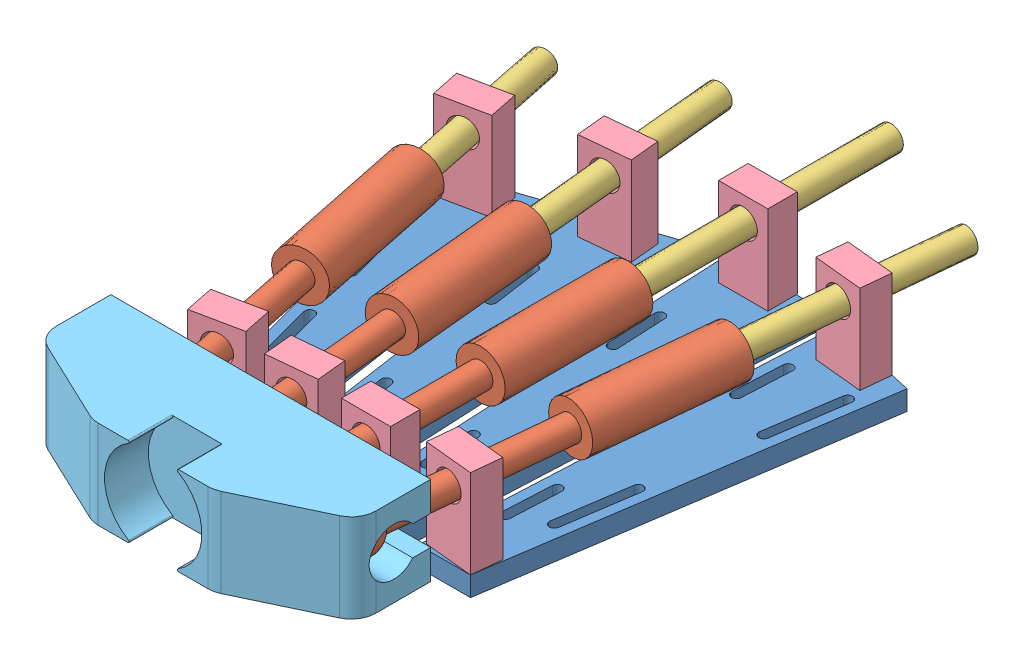
SolidWorks assembly Back_of_hand, configuration Default. Lengths in mm.
Overall size (87.18 26 139.8).
18 component instances, 5 part files, 38 mates.
Components (placement in the parent):
- Back_of_hand_base-1: Back_of_hand_base [Default] at origin size (87.18 4 82.73)
- Back_of_hand_diff_rod_outer-1: Back_of_hand_diff_rod_outer [Default] at (-35.6285 17 10.2401) x (-0.935794 -0.294771 0.193391) z (0.202383 0 0.979306) size (10 10 74.5)
- Back_of_hand_diff_rod_inner-1: Back_of_hand_diff_rod_inner [Ring] at (-17.9319 17 -4.3231) x (0.01106 -0.999938 -0.001065) z (0.095828 0 0.995398) size (5 5 50)
- Back_of_hand_diff_rod_outer-2: Back_of_hand_diff_rod_outer [Default] at (-16.6074 17 9.4356) x (0.587338 0.807364 -0.056544) z (0.095828 0 0.995398) size (10 10 74.5)
- Back_of_hand_diff_rod_inner-2: Back_of_hand_diff_rod_inner [Pinky] at (-38.3595 17 -2.9749) x (-0.272097 0.960626 0.056231) z (0.202383 0 0.979306) size (5 5 40)
- Back_of_hand_diff_rod_inner-3: Back_of_hand_diff_rod_inner [Middle] at (2.1823 17 -4.1955) x (-0.866819 -0.498624 -0.000178) z (-0.000206 0 1) size (5 5 60)
- Back_of_hand_diff_rod_outer-3: Back_of_hand_diff_rod_outer [Default] at (2.1796 17 9.2055) x (0.99957 0.029339 0.000206) z (-0.000206 0 1) size (10 10 74.5)
- Back_of_hand_diff_rod_inner-4: Back_of_hand_diff_rod_inner [Index] at (22.9884 17 -4.1612) x (0.887656 -0.452116 0.087506) z (-0.098105 0 0.995176) size (5 5 50)
- Back_of_hand_diff_rod_outer-4: Back_of_hand_diff_rod_outer [Default] at (21.647 17 9.4467) x (0.691392 -0.719257 0.068158) z (-0.098105 0 0.995176) size (10 10 74.5)
- Back_of_hand_bar_holder-1: Back_of_hand_bar_holder [Default] at (-20.8258 17 -34.3829) x (0.995398 0 -0.095828) z (0.095828 0 0.995398) size (10 18 6)
- Back_of_hand_bar_holder-2: Back_of_hand_bar_holder [Default] at (-14.0453 17 36.0485) x (0.995398 0 -0.095828) z (0.095828 0 0.995398) size (10 18 6)
- Back_of_hand_bar_holder-3: Back_of_hand_bar_holder [Default] at (19.0255 17 36.0384) x (0.995176 0 0.098105) z (-0.098105 0 0.995176) size (10 18 6)
- Back_of_hand_bar_holder-4: Back_of_hand_bar_holder [Default] at (26.1272 17 -36.0008) x (0.995176 0 0.098105) z (-0.098105 0 0.995176) size (10 18 6)
- Back_of_hand_bar_holder-5: Back_of_hand_bar_holder [Default] at (2.1897 17 -40.1452) x (1 0 0.000206) z (-0.000206 0 1) size (10 18 6)
- Back_of_hand_bar_holder-6: Back_of_hand_bar_holder [Default] at (2.1739 17 36.501) x (1 0 0.000206) z (-0.000206 0 1) size (10 18 6)
- Back_of_hand_bar_holder-7: Back_of_hand_bar_holder [Default] at (-43.411 17 -27.4181) x (0.979306 0 -0.202383) z (0.202383 0 0.979306) size (10 18 6)
- Back_of_hand_bar_holder-8: Back_of_hand_bar_holder [Default] at (-30.3851 17 35.6122) x (0.979306 0 -0.202383) z (0.202383 0 0.979306) size (10 18 6)
- Back_of_hand_bar_connector-1: Back_of_hand_bar_connector [Default] at (-40.4652 17 59.2055) size (65 18 23.9)
Mates (geometry in assembly coordinates):
- Coincident2: coordinate: point of Back_of_hand_base-1; point of assembly
- Concentric1: concentric anti-aligned: cylinder of Back_of_hand_diff_rod_inner-4 through (29.1691 17 -66.8573) axis (0.098105 0 -0.995176) radius 2.5; cylinder of Back_of_hand_diff_rod_outer-4 through (17.004 17 56.5449) axis (-0.098105 0 0.995176) radius 2.5
- Concentric2: concentric anti-aligned: cylinder of Back_of_hand_diff_rod_inner-1 through (-23.9691 17 -67.0332) axis (-0.095828 0 -0.995398) radius 2.5; cylinder of Back_of_hand_diff_rod_outer-2 through (-12.0722 17 56.5443) axis (0.095828 0 0.995398) radius 2.5
- Concentric3: concentric anti-aligned: cylinder of Back_of_hand_diff_rod_outer-1 through (-26.0504 17 56.5873) axis (0.202383 0 0.979306) radius 2.5; cylinder of Back_of_hand_diff_rod_inner-2 through (-51.1097 17 -64.6712) axis (-0.202383 0 -0.979306) radius 2.5
- Concentric4: concentric anti-aligned: cylinder of Back_of_hand_diff_rod_inner-3 through (2.1953 17 -67.1955) axis (0.000206 0 -1) radius 2.5; cylinder of Back_of_hand_diff_rod_outer-3 through (2.1698 17 56.532) axis (-0.000206 0 1) radius 2.5
- Concentric5: concentric anti-aligned: cylinder of Back_of_hand_diff_rod_outer-1 through (-26.0504 17 56.5873) axis (0.202383 0 0.979306) radius 2.5; cylinder of Back_of_hand_bar_holder-8 through (-29.1708 17 41.4881) axis (-0.202383 0 -0.979306) radius 2.875
- Concentric6: concentric aligned: cylinder of Back_of_hand_diff_rod_inner-2 through (-51.1097 17 -64.6712) axis (-0.202383 0 -0.979306) radius 2.5; cylinder of Back_of_hand_bar_holder-7 through (-42.1967 17 -21.5423) axis (-0.202383 0 -0.979306) radius 2.875
- Concentric7: concentric aligned: cylinder of Back_of_hand_diff_rod_inner-1 through (-23.9691 17 -67.0332) axis (-0.095828 0 -0.995398) radius 2.5; cylinder of Back_of_hand_bar_holder-1 through (-20.2508 17 -28.4105) axis (-0.095828 0 -0.995398) radius 2.875
- Concentric8: concentric anti-aligned: cylinder of Back_of_hand_diff_rod_outer-3 through (2.1698 17 56.532) axis (-0.000206 0 1) radius 2.5; cylinder of Back_of_hand_bar_holder-6 through (2.1727 17 42.501) axis (0.000206 0 -1) radius 2.875
- Concentric9: concentric aligned: cylinder of Back_of_hand_diff_rod_inner-3 through (2.1953 17 -67.1955) axis (0.000206 0 -1) radius 2.5; cylinder of Back_of_hand_bar_holder-5 through (2.1885 17 -34.1452) axis (0.000206 0 -1) radius 2.875
- Concentric10: concentric aligned: cylinder of Back_of_hand_diff_rod_inner-4 through (29.1691 17 -66.8573) axis (0.098105 0 -0.995176) radius 2.5; cylinder of Back_of_hand_bar_holder-3 through (18.4369 17 42.0095) axis (0.098105 0 -0.995176) radius 2.875
- Concentric11: concentric aligned: cylinder of Back_of_hand_diff_rod_inner-4 through (29.1691 17 -66.8573) axis (0.098105 0 -0.995176) radius 2.5; cylinder of Back_of_hand_bar_holder-4 through (25.5386 17 -30.0297) axis (0.098105 0 -0.995176) radius 2.875
- Concentric12: concentric: sphere of Back_of_hand_diff_rod_outer-4; cylinder of Back_of_hand_bar_connector-1 through (24.5348 17 59.2055) axis (-1 0 0) radius 4.875
- Concentric13: concentric: sphere of Back_of_hand_diff_rod_outer-3; cylinder of Back_of_hand_bar_connector-1 through (24.5348 17 59.2055) axis (-1 0 0) radius 4.875
- Parallel6: parallel aligned: plane of Back_of_hand_base-1 through (23.4128 4 42.5) normal (0 0 1); plane of Back_of_hand_bar_connector-1 through (24.5348 26 75.6055) normal (0 0 1)
- Parallel7: parallel anti-aligned: line of Back_of_hand_base-1 through (25.9082 4 -36.6777) axis (-0.098105 0 0.995176); cylinder of Back_of_hand_diff_rod_inner-4 through (29.1691 17 -66.8573) axis (0.098105 0 -0.995176) radius 2.5
- Parallel8: parallel anti-aligned: line of Back_of_hand_base-1 through (2.4997 4 -40.0367) axis (-0.000206 0 1); cylinder of Back_of_hand_diff_rod_inner-3 through (2.1953 17 -67.1955) axis (0.000206 0 -1) radius 2.5
- Parallel9: parallel anti-aligned: line of Back_of_hand_base-1 through (-20.6578 4 -35.6178) axis (0.095828 0 0.995398); cylinder of Back_of_hand_diff_rod_inner-1 through (-23.9691 17 -67.0332) axis (-0.095828 0 -0.995398) radius 2.5
- Parallel10: parallel anti-aligned: line of Back_of_hand_base-1 through (-43.3395 4 -28.0613) axis (0.202383 0 0.979306); cylinder of Back_of_hand_diff_rod_inner-2 through (-51.1097 17 -64.6712) axis (-0.202383 0 -0.979306) radius 2.5
- Coincident9: coincident anti-aligned: plane of Back_of_hand_base-1 through (0 4 0) normal (0 1 0); plane of Back_of_hand_bar_holder-8 through (-34.0674 4 42.5) normal (0 -1 0)
- Coincident10: coincident anti-aligned: plane of Back_of_hand_base-1 through (0 4 0) normal (0 1 0); plane of Back_of_hand_bar_holder-2 through (-18.4473 4 42.5) normal (0 -1 0)
- Concentric14: concentric anti-aligned: cylinder of Back_of_hand_diff_rod_outer-2 through (-12.0722 17 56.5443) axis (0.095828 0 0.995398) radius 2.5; cylinder of Back_of_hand_bar_holder-2 through (-13.4703 17 42.0209) axis (-0.095828 0 -0.995398) radius 2.875
- Coincident12: coincident anti-aligned: plane of Back_of_hand_base-1 through (0 4 0) normal (0 1 0); plane of Back_of_hand_bar_holder-6 through (-2.8273 4 42.5) normal (0 -1 0)
- Coincident13: coincident anti-aligned: plane of Back_of_hand_base-1 through (0 4 0) normal (0 1 0); plane of Back_of_hand_bar_holder-3 through (13.461 4 41.5189) normal (0 -1 0)
- Coincident14: coincident anti-aligned: line of Back_of_hand_base-1 through (23.4128 4 42.5) axis (0 -1 0); line of Back_of_hand_bar_holder-3 through (23.4128 4 42.5) axis (0 1 0)
- Coincident15: coincident aligned: line of Back_of_hand_base-1 through (-34.0674 4 42.5) axis (0 -1 0); line of Back_of_hand_bar_holder-8 through (-34.0674 22 42.5) axis (0 -1 0)
- Coincident17: coincident aligned: line of Back_of_hand_base-1 through (-18.4473 4 42.5) axis (0 -1 0); line of Back_of_hand_bar_holder-2 through (-18.4473 22 42.5) axis (0 -1 0)
- Coincident18: coincident aligned: line of Back_of_hand_base-1 through (-2.8273 4 42.5) axis (0 -1 0); line of Back_of_hand_bar_holder-6 through (-2.8273 22 42.5) axis (0 -1 0)
- Concentric15: concentric: sphere of Back_of_hand_diff_rod_outer-2; cylinder of Back_of_hand_bar_connector-1 through (24.5348 17 59.2055) axis (-1 0 0) radius 4.875
- Concentric16: concentric: sphere of Back_of_hand_diff_rod_outer-1; cylinder of Back_of_hand_bar_connector-1 through (24.5348 17 59.2055) axis (-1 0 0) radius 4.875
- Coincident19: coincident anti-aligned: plane of Back_of_hand_base-1 through (0 4 0) normal (0 1 0); plane of Back_of_hand_bar_holder-7 through (-47.0932 4 -20.5304) normal (0 -1 0)
- Coincident20: coincident anti-aligned: plane of Back_of_hand_base-1 through (0 4 0) normal (0 1 0); plane of Back_of_hand_bar_holder-1 through (-25.2278 4 -27.9313) normal (0 -1 0)
- Coincident21: coincident anti-aligned: plane of Back_of_hand_base-1 through (0 4 0) normal (0 1 0); plane of Back_of_hand_bar_holder-5 through (-2.8115 4 -34.1463) normal (0 -1 0)
- Coincident22: coincident anti-aligned: plane of Back_of_hand_base-1 through (0 4 0) normal (0 1 0); plane of Back_of_hand_bar_holder-4 through (20.5627 4 -30.5203) normal (0 -1 0)
- Coincident24: coincident: line of Back_of_hand_base-1 through (-34.4987 4 -31.0067) axis (-0.948735 0 0.316074); point of Back_of_hand_bar_holder-7
- Coincident25: coincident: line of Back_of_hand_base-1 through (-11.8169 4 -38.5632) axis (-0.948735 0 0.316074); point of Back_of_hand_bar_holder-1
- Coincident26: coincident: line of Back_of_hand_base-1 through (11.8163 4 -39.8445) axis (-0.999787 0 -0.020624); point of Back_of_hand_bar_holder-5
- Coincident29: coincident: plane of Back_of_hand_base-1 through (16.8163 4 -38.7209) normal (0.219259 0 -0.975667); line of Back_of_hand_bar_holder-4 through (31.1031 4 -35.5103) axis (0 1 0)
